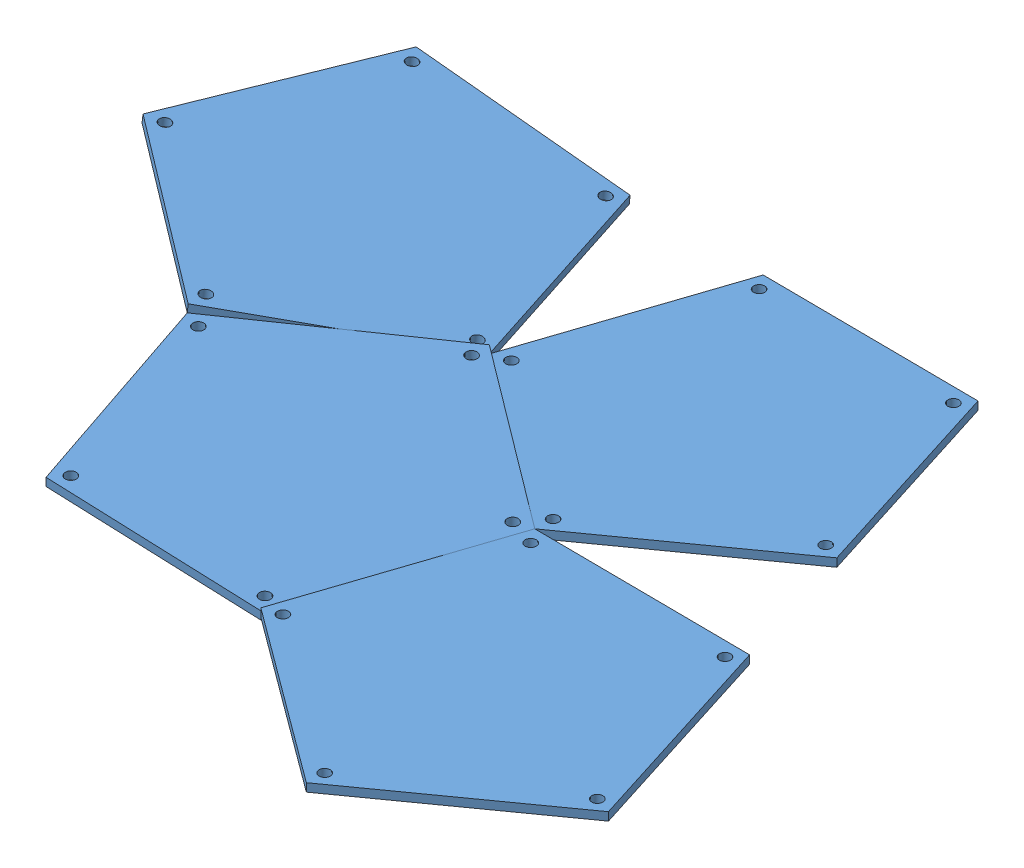
SolidWorks assembly ACMboard, configuration Default. Lengths in mm.
Overall size (1142.68 125.53 998.29).
4 component instances, 1 part files, 5 mates.
Components (placement in the parent):
- robotstackplate-1: robotstackplate [Default] at (107.2522 194.5212 405.052) size (470.21 11 448.34)
- robotstackplate-2: robotstackplate [Default] at (-130.4806 200.0231 726.7399) x (0.808441 -0.037836 0.58736) z (-0.58779 -0.000297 0.809014) size (470.21 11 448.34)
- robotstackplate-3: robotstackplate [Default] at (-362.1536 225.3887 401.4631) x (-0.320329 0.050022 0.945985) z (0.942844 -0.079975 0.323495) size (470.21 11 448.34)
- robotstackplate-4: robotstackplate [Default] at (249.0429 194.5212 853.3933) size (470.21 11 448.34)
Mates (geometry in assembly coordinates):
- Coincident1: coincident anti-aligned: plane of robotstackplate-1 through (-128.4548 205.5212 479.5958) normal (-0.594123 0 0.804374); plane of robotstackplate-2 through (105.4775 205.5172 652.3816) normal (0.594123 0 -0.804374)
- Coincident2: coincident: point of robotstackplate-1; unknown of robotstackplate-2
- Coincident3: coincident: unknown of robotstackplate-1; unknown of robotstackplate-4
- Coincident4: coincident: point of robotstackplate-1; point of robotstackplate-3
- Coincident6: coincident: point of robotstackplate-2; point of robotstackplate-3
